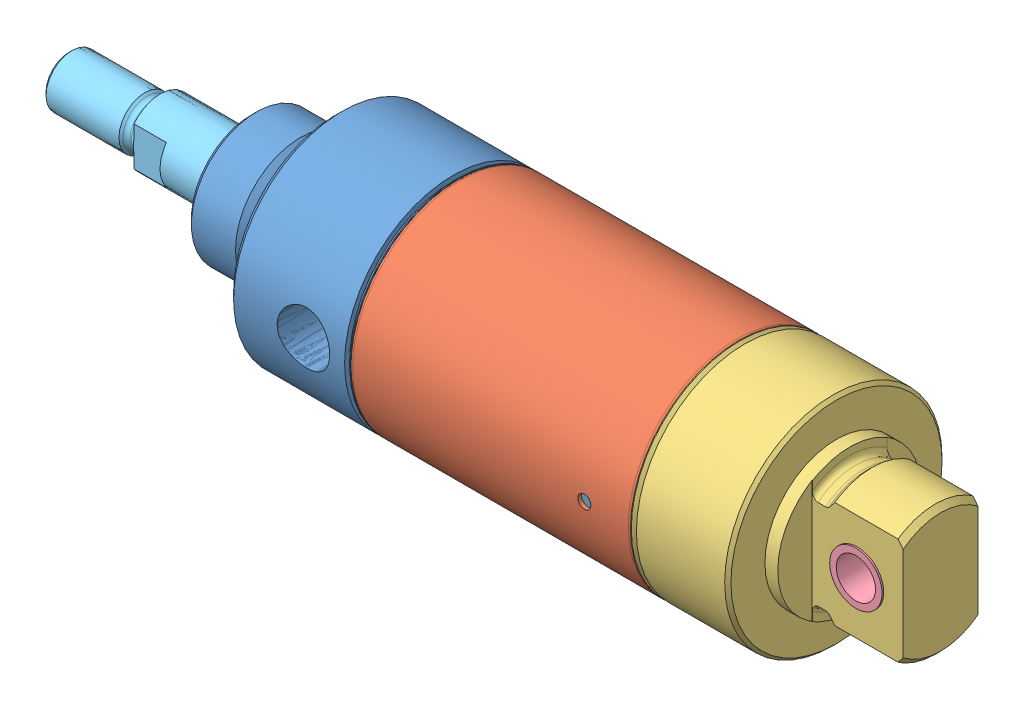
SolidWorks assembly Assem4, configuration Default. Lengths in mm.
Overall size (212.42 52.97 52.97).
6 component instances, 6 part files, 14 mates.
Components (placement in the parent):
- 310_5-RPC0000_0_dummy-1: 310_5-RPC0000_0_dummy [Default] at origin
- 31R000-0_5_rod_guide-1: 31R000-0_5_rod_guide [Default] at origin size (58.72 52.97 52.97)
- 31R-2_7173C-1: 31R-2_7173C [Default] at (50.2539 0 0) size (70.92 52.97 52.97)
- 31PR0Y000_rear_head-1: 31PR0Y000_rear_head [Default] at (112.395 0 0) size (55.58 52.97 52.97)
- D-624-5-1: D-624-5 [Default] at (156.845 0 0) x (1 0 0) z (0 0 -1) size (12.76 12.76 19.05)
- C-310_5-RP0_rod-1: C-310_5-RP0_rod [Default] at (-12.7 0 0) size (144.14 51.04 51.04)
Mates (geometry in assembly coordinates):
- Distance2: distance = 0 mm aligned: plane of 31R000-0_5_rod_guide-1 through (0 0 0) normal (1 0 0); plane of 310_5-RPC0000_0_dummy-1 through (0 0 0) normal (1 0 0)
- Coincident1: coincident aligned: line of 310_5-RPC0000_0_dummy-1 through (80.9 0 0) axis (-1 0 0); line of 31R000-0_5_rod_guide-1 through (80.9 0 0) axis (-1 0 0)
- Angle3: planar angle = 0 rad aligned: plane of 31R000-0_5_rod_guide-1 through (0 0 0) normal (0 0 -1); plane of 310_5-RPC0000_0_dummy-1 through (0 0 0) normal (0 0 -1)
- Distance4: distance = 0 mm aligned: plane of 31R-2_7173C-1 through (50.2539 0 0) normal (1 0 0); plane of 31R000-0_5_rod_guide-1 through (50.2539 0 0) normal (1 0 0)
- Coincident2: coincident aligned: line of 31R000-0_5_rod_guide-1 through (80.9 0 0) axis (-1 0 0); line of 31R-2_7173C-1 through (131.1539 0 0) axis (-1 0 0)
- Angle6: planar angle = 0 rad aligned: plane of 31R-2_7173C-1 through (50.2539 0 0) normal (0 0 -1); plane of 31R000-0_5_rod_guide-1 through (0 0 0) normal (0 0 -1)
- Distance6: distance = 0 mm aligned: plane of 31PR0Y000_rear_head-1 through (119.2657 0 0) normal (1 0 0); plane of 31R-2_7173C-1 through (119.2657 0 0) normal (1 0 0)
- Coincident3: coincident aligned: line of 31R-2_7173C-1 through (131.1539 0 0) axis (-1 0 0); line of 31PR0Y000_rear_head-1 through (193.295 0 0) axis (-1 0 0)
- Angle9: planar angle = 0 rad aligned: plane of 31PR0Y000_rear_head-1 through (112.395 0 0) normal (0 0 -1); plane of 31R-2_7173C-1 through (50.2539 0 0) normal (0 0 -1)
- Distance7: distance = 0 mm anti-aligned: plane of D-624-5-1 through (156.845 0 0) normal (0 0 -1); plane of 31PR0Y000_rear_head-1 through (112.395 0 0) normal (0 0 1)
- Coincident4: coincident anti-aligned: line of 31PR0Y000_rear_head-1 through (156.845 0 80.9) axis (0 0 -1); line of D-624-5-1 through (156.845 0 -80.9) axis (0 0 1)
- Angle12: planar angle = 0 rad aligned: plane of D-624-5-1; plane of 31PR0Y000_rear_head-1 through (156.845 0 0) normal (1 0 0)
- LimitDistance2: limit distance = 0 mm aligned: plane of C-310_5-RP0_rod-1 through (-12.7 0 0) normal (1 0 0); plane of 31R000-0_5_rod_guide-1 through (-12.7 0 0) normal (1 0 0)
- Coincident5: coincident aligned: line of 31R000-0_5_rod_guide-1 through (80.9 0 0) axis (-1 0 0); line of C-310_5-RP0_rod-1 through (68.2 0 0) axis (-1 0 0)
